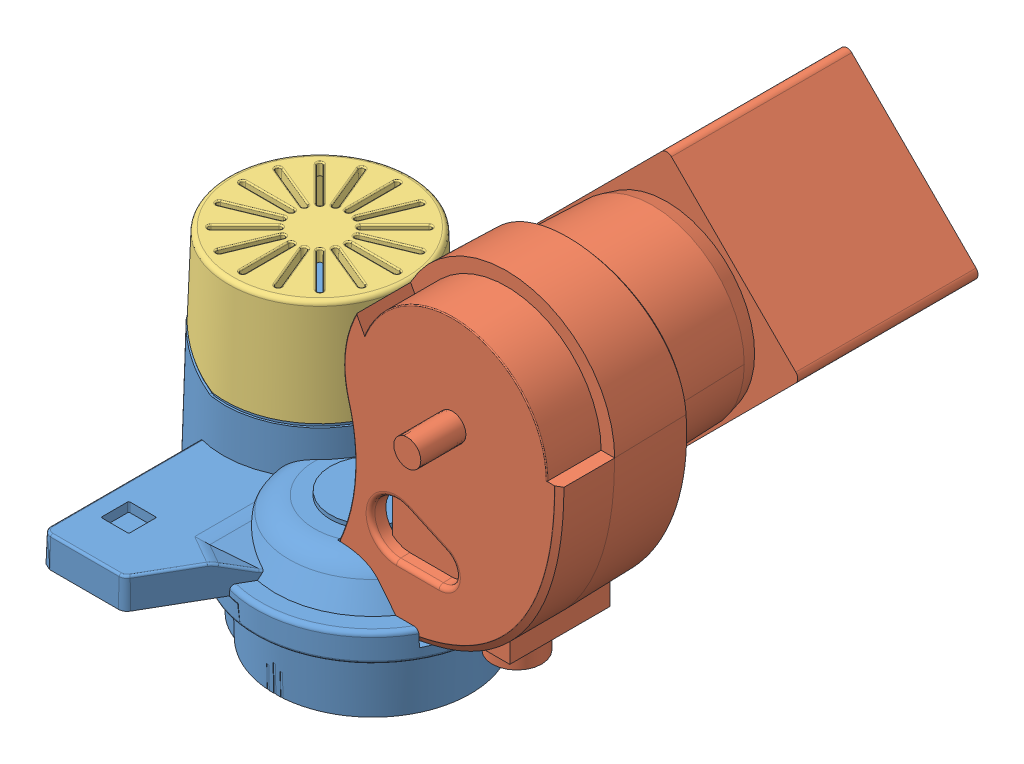
SolidWorks assembly Mirobot_Link1, configuration 默认. Lengths in mm.
Overall size (114.93 90.38 115.48).
3 component instances, 3 part files, 5 mates.
Components (placement in the parent):
- 04旋转底座-2: 04旋转底座 [默认] at (0.2776 -9.246 77.9265) x (1 0 0) z (0 1 0) size (75.38 77.6 46.2)
- 05支撑底座-1: 05支撑底座 [默认] at (37.6662 26.4117 76.5499) x (-1 0 0) z (0 0 -1) size (60.2 76.87 97.54)
- 1关节盖-2: 1关节盖 [默认] at (15.6589 10.9772 42.2526) x (0.5 0 0.866025) z (0 1 0) size (41.83 41.33 23.09)
Mates (geometry in assembly coordinates):
- 同心2: concentric aligned: cylinder of 04旋转底座-2 through (27.634 4.154 81.4615) axis (0 -1 0) radius 1.1002; cylinder of 05支撑底座-1 through (27.634 -7.446 81.4615) axis (0 -1 0) radius 1.1
- 重合3: coincident anti-aligned: plane of 04旋转底座-2 through (30.634 -7.446 88.4615) normal (0 1 0); plane of 05支撑底座-1 through (11.634 -7.446 76.4615) normal (0 -1 0)
- 同心3: concentric anti-aligned: cone of 1关节盖-2 through (-16.0788 10.9772 60.4615) axis (0 1 0); cylinder of 04旋转底座-2 through (-16.0788 23.154 60.4615) axis (0 -1 0) radius 19
- 重合4: coincident: plane of 04旋转底座-2 through (12.6272 10.9772 26.2768) normal (0 1 0); plane of 1关节盖-2 through (12.6272 10.9772 26.2768) normal (0 -1 0)
- 重合5: coincident anti-aligned: plane of 04旋转底座-2 through (2.3564 15.755 20.3966) normal (0.332056 0.923903 0.19011); plane of 1关节盖-2 through (2.3564 15.755 20.3966) normal (-0.332056 -0.923903 -0.19011)
